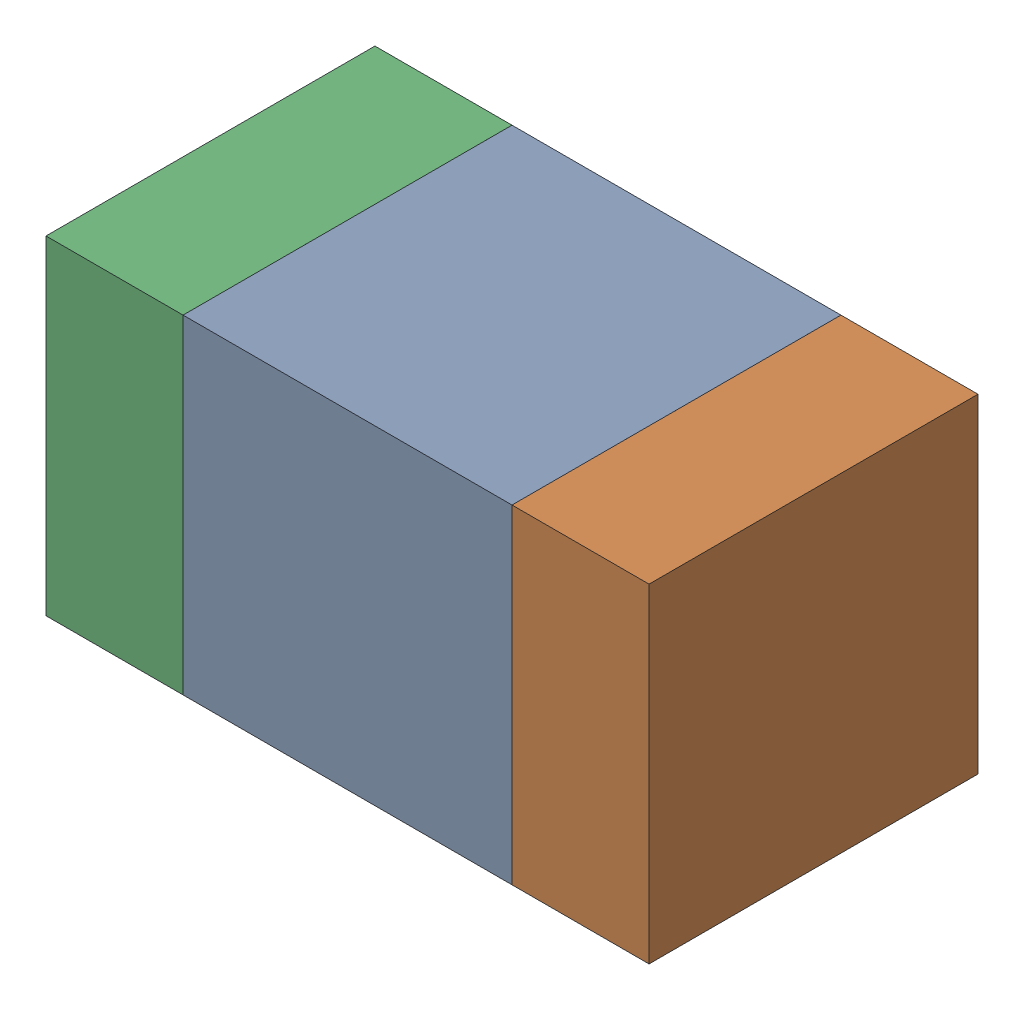
SolidWorks assembly C501_1PCB, configuration Default. Lengths in mm.
Overall size (1.1 0.6 0.6).
6 component instances, 2 part files, 0 mates.
Components (placement in the parent):
- 761606048-1: 761606048 [Default] at (147.2 117.8 0) size (0.6 0.6 0.6)
  - Extruded_9-1: Extruded_9 [Default] at origin size (0.6 0.6 0.6)
- 854785160-1: 854785160 [Default] at (147.625 117.8 0) size (0.25 0.6 0.6)
  - Extruded_19-1: Extruded_19 [Default] at origin size (0.25 0.6 0.6)
- 854785160-2: 854785160 [Default] at (146.775 117.8 0) size (0.25 0.6 0.6)
  - Extruded_19-1: Extruded_19 [Default] at origin size (0.25 0.6 0.6)
